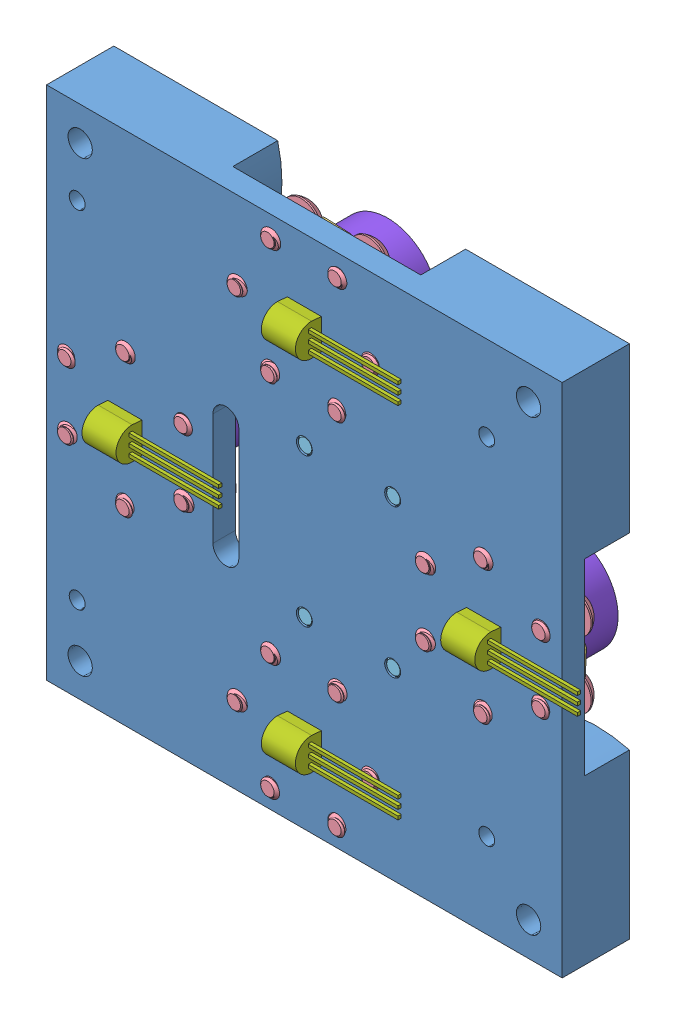
SolidWorks assembly LED Camera Assembly, configuration Default. Lengths in mm.
Overall size (79.31 74.9 15.88).
54 component instances, 9 part files, 49 mates.
Components (placement in the parent):
- Camera LED Holder Plate-1: Camera LED Holder Plate [Default] at (-0.0586 0.0315 12.2) x (1 0 0) z (0 1 0) size (73.03 9.53 73.03)
- RasPi_Camera-2: RasPi_Camera [Default] at (-0.0586 0.0315 4.3983) x (0 -1 0) z (1 0 0) size (25 8.25 24)
- COM-1318-5: COM-1318 [Default] at (-0.0586 -25.3685 9.025) x (0.998942 -0.045987 0) z (0.045987 0.998942 0) size (19.62 5.1 20.4)
- COM-1318-2: COM-1318 [Default] at (-25.4586 0.0315 9.025) x (0.888103 0.459645 0) z (-0.459645 0.888103 0) size (19.62 5.1 20.4)
- COM-1318-3: COM-1318 [Default] at (-0.0586 25.4315 9.025) x (0.998942 -0.045987 0) z (0.045987 0.998942 0) size (19.62 5.1 20.4)
- COM-1318-4: COM-1318 [Default] at (25.3414 0.0315 9.025) x (0.888103 0.459645 0) z (-0.459645 0.888103 0) size (19.62 5.1 20.4)
- 91255A105_ALLOY STEEL BUTTON-HEAD SOCKET CAP SCREW-1: 91255A105_ALLOY STEEL BUTTON-HEAD SOCKET CAP SCREW [91255A105] at (33.5686 -4.7185 6.4264) x (-0.805976 0.591949 0) z (0 0 -1) size (5.41 5.41 6.56)
- 91255A105_ALLOY STEEL BUTTON-HEAD SOCKET CAP SCREW-2: 91255A105_ALLOY STEEL BUTTON-HEAD SOCKET CAP SCREW [91255A105] at (25.3414 -9.4685 6.4264) x (0.109655 0.99397 0) z (0 0 -1) size (5.41 5.41 6.56)
- 91255A105_ALLOY STEEL BUTTON-HEAD SOCKET CAP SCREW-3: 91255A105_ALLOY STEEL BUTTON-HEAD SOCKET CAP SCREW [91255A105] at (17.1141 -4.7185 6.4264) x (0.91563 0.402021 0) z (0 0 -1) size (5.41 5.41 6.56)
- 91255A105_ALLOY STEEL BUTTON-HEAD SOCKET CAP SCREW-4: 91255A105_ALLOY STEEL BUTTON-HEAD SOCKET CAP SCREW [91255A105] at (17.1141 4.7815 6.4264) x (0.805976 -0.591949 0) z (0 0 -1) size (5.41 5.41 6.56)
- 91255A105_ALLOY STEEL BUTTON-HEAD SOCKET CAP SCREW-5: 91255A105_ALLOY STEEL BUTTON-HEAD SOCKET CAP SCREW [91255A105] at (25.3414 9.5315 6.4264) x (-0.109655 -0.99397 0) z (0 0 -1) size (5.41 5.41 6.56)
- 91255A105_ALLOY STEEL BUTTON-HEAD SOCKET CAP SCREW-6: 91255A105_ALLOY STEEL BUTTON-HEAD SOCKET CAP SCREW [91255A105] at (33.5686 4.7815 6.4264) x (-0.91563 -0.402021 0) z (0 0 -1) size (5.41 5.41 6.56)
- 91255A105_ALLOY STEEL BUTTON-HEAD SOCKET CAP SCREW-7: 91255A105_ALLOY STEEL BUTTON-HEAD SOCKET CAP SCREW [91255A105] at (-33.5686 -4.7185 6.4264) x (0.805976 0.591949 0) z (0 0 -1) size (5.41 5.41 6.56)
- 91255A105_ALLOY STEEL BUTTON-HEAD SOCKET CAP SCREW-8: 91255A105_ALLOY STEEL BUTTON-HEAD SOCKET CAP SCREW [91255A105] at (-25.3414 -9.4685 6.4264) x (-0.109655 0.99397 0) z (0 0 -1) size (5.41 5.41 6.56)
- 91255A105_ALLOY STEEL BUTTON-HEAD SOCKET CAP SCREW-9: 91255A105_ALLOY STEEL BUTTON-HEAD SOCKET CAP SCREW [91255A105] at (-17.1141 -4.7185 6.4264) x (0.91563 -0.402021 0) z (0 0 -1) size (5.41 5.41 6.56)
- 91255A105_ALLOY STEEL BUTTON-HEAD SOCKET CAP SCREW-10: 91255A105_ALLOY STEEL BUTTON-HEAD SOCKET CAP SCREW [91255A105] at (-17.1141 4.7815 6.4264) x (-0.805976 -0.591949 0) z (0 0 -1) size (5.41 5.41 6.56)
- 91255A105_ALLOY STEEL BUTTON-HEAD SOCKET CAP SCREW-11: 91255A105_ALLOY STEEL BUTTON-HEAD SOCKET CAP SCREW [91255A105] at (-25.3414 9.5315 6.4264) x (0.109655 -0.99397 0) z (0 0 -1) size (5.41 5.41 6.56)
- 91255A105_ALLOY STEEL BUTTON-HEAD SOCKET CAP SCREW-12: 91255A105_ALLOY STEEL BUTTON-HEAD SOCKET CAP SCREW [91255A105] at (-33.5686 4.7815 6.4264) x (-0.91563 0.402021 0) z (0 0 -1) size (5.41 5.41 6.56)
- 91255A105_ALLOY STEEL BUTTON-HEAD SOCKET CAP SCREW-13: 91255A105_ALLOY STEEL BUTTON-HEAD SOCKET CAP SCREW [91255A105] at (9.4414 25.4315 6.4264) x (-0.991393 -0.130919 0) z (0 0 -1) size (5.41 5.41 6.56)
- 91255A105_ALLOY STEEL BUTTON-HEAD SOCKET CAP SCREW-14: 91255A105_ALLOY STEEL BUTTON-HEAD SOCKET CAP SCREW [91255A105] at (4.6914 17.2043 6.4264) x (-0.609075 0.793112 0) z (0 0 -1) size (5.41 5.41 6.56)
- 91255A105_ALLOY STEEL BUTTON-HEAD SOCKET CAP SCREW-15: 91255A105_ALLOY STEEL BUTTON-HEAD SOCKET CAP SCREW [91255A105] at (-4.8086 17.2043 6.4264) x (0.382318 0.924031 0) z (0 0 -1) size (5.41 5.41 6.56)
- 91255A105_ALLOY STEEL BUTTON-HEAD SOCKET CAP SCREW-16: 91255A105_ALLOY STEEL BUTTON-HEAD SOCKET CAP SCREW [91255A105] at (-9.5586 25.4315 6.4264) x (0.991393 0.130919 0) z (0 0 -1) size (5.41 5.41 6.56)
- 91255A105_ALLOY STEEL BUTTON-HEAD SOCKET CAP SCREW-17: 91255A105_ALLOY STEEL BUTTON-HEAD SOCKET CAP SCREW [91255A105] at (-4.8086 33.6588 6.4264) x (0.609075 -0.793112 0) z (0 0 -1) size (5.41 5.41 6.56)
- 91255A105_ALLOY STEEL BUTTON-HEAD SOCKET CAP SCREW-18: 91255A105_ALLOY STEEL BUTTON-HEAD SOCKET CAP SCREW [91255A105] at (4.6914 33.6588 6.4264) x (-0.382318 -0.924031 0) z (0 0 -1) size (5.41 5.41 6.56)
- 91255A105_ALLOY STEEL BUTTON-HEAD SOCKET CAP SCREW-19: 91255A105_ALLOY STEEL BUTTON-HEAD SOCKET CAP SCREW [91255A105] at (9.4414 -25.4315 6.4264) x (-0.991393 0.130919 0) z (0 0 -1) size (5.41 5.41 6.56)
- 91255A105_ALLOY STEEL BUTTON-HEAD SOCKET CAP SCREW-20: 91255A105_ALLOY STEEL BUTTON-HEAD SOCKET CAP SCREW [91255A105] at (4.6914 -17.2043 6.4264) x (0.609075 0.793112 0) z (0 0 -1) size (5.41 5.41 6.56)
- 91255A105_ALLOY STEEL BUTTON-HEAD SOCKET CAP SCREW-21: 91255A105_ALLOY STEEL BUTTON-HEAD SOCKET CAP SCREW [91255A105] at (-4.8086 -17.2043 6.4264) x (0.382318 -0.924031 0) z (0 0 -1) size (5.41 5.41 6.56)
- 91255A105_ALLOY STEEL BUTTON-HEAD SOCKET CAP SCREW-22: 91255A105_ALLOY STEEL BUTTON-HEAD SOCKET CAP SCREW [91255A105] at (-9.5586 -25.4315 6.4264) x (0.991393 -0.130919 0) z (0 0 -1) size (5.41 5.41 6.56)
- 91255A105_ALLOY STEEL BUTTON-HEAD SOCKET CAP SCREW-23: 91255A105_ALLOY STEEL BUTTON-HEAD SOCKET CAP SCREW [91255A105] at (-4.8086 -33.6588 6.4264) x (-0.609075 -0.793112 0) z (0 0 -1) size (5.41 5.41 6.56)
- 91255A105_ALLOY STEEL BUTTON-HEAD SOCKET CAP SCREW-24: 91255A105_ALLOY STEEL BUTTON-HEAD SOCKET CAP SCREW [91255A105] at (4.6914 -33.6588 6.4264) x (-0.382318 0.924031 0) z (0 0 -1) size (5.41 5.41 6.56)
- 94735A152_BLACK NYLON PAN HEAD MACHINE SCREW-1: 94735A152_BLACK NYLON PAN HEAD MACHINE SCREW [94735A152] at (-0.0586 10.5315 4.95) x (-0.923728 -0.383049 0) z (0 0 -1) size (5.46 5.57 9.5)
- 94735A152_BLACK NYLON PAN HEAD MACHINE SCREW-2: 94735A152_BLACK NYLON PAN HEAD MACHINE SCREW [94735A152] at (12.4414 10.5315 4.95) x (-0.923728 -0.383049 0) z (0 0 -1) size (5.46 5.57 9.5)
- 94735A152_BLACK NYLON PAN HEAD MACHINE SCREW-3: 94735A152_BLACK NYLON PAN HEAD MACHINE SCREW [94735A152] at (-0.0586 -10.4685 4.95) x (-0.923728 -0.383049 0) z (0 0 -1) size (5.46 5.57 9.5)
- 94735A152_BLACK NYLON PAN HEAD MACHINE SCREW-4: 94735A152_BLACK NYLON PAN HEAD MACHINE SCREW [94735A152] at (12.4414 -10.4685 4.95) x (-0.923728 -0.383049 0) z (0 0 -1) size (5.46 5.57 9.5)
- 94639A702_NYLON UNTHRD SPACERS-1: 94639A702_NYLON UNTHRD SPACERS [94639A702] at (12.4414 -10.4685 7.4375) size (4.76 4.76 3.17)
- 94639A702_NYLON UNTHRD SPACERS-2: 94639A702_NYLON UNTHRD SPACERS [94639A702] at (-0.0586 -10.4685 7.4375) size (4.76 4.76 3.17)
- 94639A702_NYLON UNTHRD SPACERS-3: 94639A702_NYLON UNTHRD SPACERS [94639A702] at (12.4414 10.5315 7.4375) size (4.76 4.76 3.17)
- 94639A702_NYLON UNTHRD SPACERS-4: 94639A702_NYLON UNTHRD SPACERS [94639A702] at (-0.0586 10.5315 7.4375) size (4.76 4.76 3.17)
- MCP9701-1: MCP9701 [Default] at (-0.0586 -25.3685 13.597) x (0 -1 0) z (1 0 0) size (4.57 3.68 17.53)
- MCP9701-2: MCP9701 [Default] at (-0.0586 25.4315 13.597) x (0 -1 0) z (1 0 0) size (4.57 3.68 17.53)
- MCP9701-3: MCP9701 [Default] at (-25.4586 0.0315 13.597) x (0 -1 0) z (1 0 0) size (4.57 3.68 17.53)
- MCP9701-4: MCP9701 [Default] at (25.3414 0.0315 13.597) x (0 -1 0) z (1 0 0) size (4.57 3.68 17.53)
- Reflector-6: Reflector [Default] at (-4.2786 15.2111 10.2933) x (1 0 0) z (0 1 0) size (14.29 7.67 14.29)
  - Reflector Shell-1: Reflector Shell [Default] at (4.22 3.162 10.2204) size (14.29 12.7 14.29)
  - Reflector Core-1: Reflector Core [Default] at (4.22 3.162 10.2204) size (12.7 6.72 12.7)
- Reflector-9: Reflector [Default] at (15.2111 4.2786 10.2933) x (0 -1 0) z (1 0 0) size (14.29 7.67 14.29)
  - Reflector Shell-1: Reflector Shell [Default] at (4.22 3.162 10.2204) size (14.29 12.7 14.29)
  - Reflector Core-1: Reflector Core [Default] at (4.22 3.162 10.2204) size (12.7 6.72 12.7)
- Reflector-10: Reflector [Default] at (4.2786 -15.2111 10.2933) x (-1 0 0) z (0 -1 0) size (14.29 7.67 14.29)
  - Reflector Shell-1: Reflector Shell [Default] at (4.22 3.162 10.2204) size (14.29 12.7 14.29)
  - Reflector Core-1: Reflector Core [Default] at (4.22 3.162 10.2204) size (12.7 6.72 12.7)
- Reflector-11: Reflector [Default] at (-15.2111 -4.2786 10.2933) x (0 1 0) z (-1 0 0) size (14.29 7.67 14.29)
  - Reflector Shell-1: Reflector Shell [Default] at (4.22 3.162 10.2204) size (14.29 12.7 14.29)
  - Reflector Core-1: Reflector Core [Default] at (4.22 3.162 10.2204) size (12.7 6.72 12.7)
Mates (geometry in assembly coordinates):
- Coincident7: coincident anti-aligned: plane of COM-1318-2 through (-25.4586 0.0315 9.025) normal (0 0 1); plane of Camera LED Holder Plate-1 through (-0.0586 0.0315 9.025) normal (0 0 -1)
- Coincident8: coincident anti-aligned: plane of COM-1318-5 through (-0.0586 -25.3685 9.025) normal (0 0 1); plane of Camera LED Holder Plate-1 through (-0.0586 0.0315 9.025) normal (0 0 -1)
- Coincident9: coincident anti-aligned: plane of COM-1318-3 through (-0.0586 25.4315 9.025) normal (0 0 1); plane of Camera LED Holder Plate-1 through (-0.0586 0.0315 9.025) normal (0 0 -1)
- Coincident10: coincident anti-aligned: plane of COM-1318-4 through (25.3414 0.0315 9.025) normal (0 0 1); plane of Camera LED Holder Plate-1 through (-0.0586 0.0315 9.025) normal (0 0 -1)
- Concentric61: concentric aligned: cylinder of Camera LED Holder Plate-1 through (12.4414 -10.4685 9.025) axis (0 0 -1) radius 1.1303; cylinder of RasPi_Camera-2 through (12.4414 -10.4685 5.85) axis (0 0 -1) radius 1.05
- Concentric62: concentric aligned: cylinder of Camera LED Holder Plate-1 through (12.4414 10.5315 9.025) axis (0 0 -1) radius 1.1303; cylinder of RasPi_Camera-2 through (12.4414 10.5315 5.85) axis (0 0 -1) radius 1.05
- Coincident73: coincident anti-aligned: plane of COM-1318-4 through (25.3414 0.0315 7.925) normal (0 0 -1); plane of 91255A105_ALLOY STEEL BUTTON-HEAD SOCKET CAP SCREW-1 through (31.9673 -6.8987 7.925) normal (0 0 1)
- Coincident74: coincident: axis of RasPi_Camera-2 through (0 0 1) axis (0 0 -1); plane of assembly
- Coincident75: coincident: axis of RasPi_Camera-2 through (0 0 1) axis (0 0 -1); plane of assembly
- Parallel5: parallel aligned: plane of Camera LED Holder Plate-1 through (-36.5711 36.544 9.025) normal (0 1 0); plane of assembly through (0 0 0) normal (0 1 0)
- Coincident77: coincident anti-aligned: plane of RasPi_Camera-2 through (0 -1 0) normal (0 0 -1); plane of assembly through (0 0 0) normal (0 0 1)
- Coincident78: coincident anti-aligned: plane of COM-1318-3 through (-0.0586 25.4315 7.925) normal (0 0 -1); plane of 91255A105_ALLOY STEEL BUTTON-HEAD SOCKET CAP SCREW-13 through (9.7955 22.7497 7.925) normal (0 0 1)
- Concentric78: concentric aligned: cylinder of Camera LED Holder Plate-1 through (9.4414 25.4315 9.025) axis (0 0 -1) radius 1.1303; circle of 91255A105_ALLOY STEEL BUTTON-HEAD SOCKET CAP SCREW-13
- Concentric79: concentric aligned: cylinder of Camera LED Holder Plate-1 through (4.6914 -33.5957 9.025) axis (0 0 -1) radius 1.1303; cylinder of COM-1318-5 through (4.6914 -33.5957 9.025) axis (0 0 -1) radius 2
- Concentric80: concentric aligned: cylinder of Camera LED Holder Plate-1 through (-4.8086 -33.5957 9.025) axis (0 0 -1) radius 1.1303; cylinder of COM-1318-5 through (-4.8086 -33.5957 9.025) axis (0 0 -1) radius 2
- Concentric81: concentric aligned: cylinder of Camera LED Holder Plate-1 through (-17.2314 -4.7185 9.025) axis (0 0 -1) radius 1.1303; cylinder of COM-1318-2 through (-17.2314 -4.7185 9.025) axis (0 0 -1) radius 2
- Concentric82: concentric aligned: cylinder of Camera LED Holder Plate-1 through (-25.4586 -9.4685 9.025) axis (0 0 -1) radius 1.1303; cylinder of COM-1318-2 through (-25.4586 -9.4685 9.025) axis (0 0 -1) radius 2
- Concentric83: concentric aligned: cylinder of Camera LED Holder Plate-1 through (4.6914 17.2043 9.025) axis (0 0 -1) radius 1.1303; cylinder of COM-1318-3 through (4.6914 17.2043 9.025) axis (0 0 -1) radius 2
- Concentric85: concentric aligned: cylinder of Camera LED Holder Plate-1 through (25.3414 -9.4685 9.025) axis (0 0 -1) radius 1.1303; cylinder of COM-1318-4 through (25.3414 -9.4685 9.025) axis (0 0 -1) radius 2
- Concentric86: concentric aligned: cylinder of Camera LED Holder Plate-1 through (17.1141 -4.7185 9.025) axis (0 0 -1) radius 1.1303; cylinder of COM-1318-4 through (17.1141 -4.7185 9.025) axis (0 0 -1) radius 2
- Concentric87: concentric aligned: cylinder of Camera LED Holder Plate-1 through (33.5686 -4.7185 9.025) axis (0 0 -1) radius 1.1303; circle of 91255A105_ALLOY STEEL BUTTON-HEAD SOCKET CAP SCREW-1
- Concentric89: concentric aligned: cylinder of COM-1318-3 through (-9.5586 25.4315 9.025) axis (0 0 -1) radius 2; cylinder of Camera LED Holder Plate-1 through (-9.5586 25.4315 9.025) axis (0 0 -1) radius 1.1303
- Coincident79: coincident anti-aligned: plane of Camera LED Holder Plate-1 through (-0.0586 0.0315 9.025) normal (0 0 -1); plane of 94639A702_NYLON UNTHRD SPACERS-2 through (-0.0586 -10.4685 9.025) normal (0 0 1)
- Concentric90: concentric anti-aligned: cylinder of Camera LED Holder Plate-1 through (-0.0586 -10.4685 9.025) axis (0 0 -1) radius 1.1303; circle of 94639A702_NYLON UNTHRD SPACERS-2
- Coincident80: coincident anti-aligned: plane of Camera LED Holder Plate-1 through (-0.0586 0.0315 9.025) normal (0 0 -1); plane of 94639A702_NYLON UNTHRD SPACERS-4 through (-0.0586 10.5315 9.025) normal (0 0 1)
- Concentric91: concentric anti-aligned: cylinder of Camera LED Holder Plate-1 through (-0.0586 10.5315 9.025) axis (0 0 -1) radius 1.1303; circle of 94639A702_NYLON UNTHRD SPACERS-4
- Coincident81: coincident anti-aligned: plane of Camera LED Holder Plate-1 through (-0.0586 0.0315 9.025) normal (0 0 -1); plane of 94639A702_NYLON UNTHRD SPACERS-1 through (12.4414 -10.4685 9.025) normal (0 0 1)
- Concentric92: concentric aligned: cylinder of Camera LED Holder Plate-1 through (12.4414 -10.4685 9.025) axis (0 0 -1) radius 1.1303; cylinder of 94639A702_NYLON UNTHRD SPACERS-1 through (12.4414 -10.4685 9.025) axis (0 0 -1) radius 2.3813
- Coincident82: coincident anti-aligned: plane of Camera LED Holder Plate-1 through (-0.0586 0.0315 9.025) normal (0 0 -1); plane of 94639A702_NYLON UNTHRD SPACERS-3 through (12.4414 10.5315 9.025) normal (0 0 1)
- Concentric93: concentric aligned: cylinder of Camera LED Holder Plate-1 through (12.4414 10.5315 9.025) axis (0 0 -1) radius 1.1303; cylinder of 94639A702_NYLON UNTHRD SPACERS-3 through (12.4414 10.5315 9.025) axis (0 0 -1) radius 2.3813
- Coincident83: coincident anti-aligned: plane of RasPi_Camera-2 through (-0.0586 0.0315 5.85) normal (0 0 1); plane of 94639A702_NYLON UNTHRD SPACERS-3 through (12.4414 10.5315 5.85) normal (0 0 -1)
- Coincident84: coincident anti-aligned: plane of RasPi_Camera-2 through (-0.0586 0.0315 4.95) normal (0 0 -1); plane of 94735A152_BLACK NYLON PAN HEAD MACHINE SCREW-4 through (12.4414 -10.4685 4.95) normal (0 0 1)
- Concentric94: concentric anti-aligned: circle of RasPi_Camera-2; cylinder of 94735A152_BLACK NYLON PAN HEAD MACHINE SCREW-4 through (12.4414 -10.4685 3.045) axis (0 0 1) radius 2.7305
- Coincident85: coincident anti-aligned: plane of RasPi_Camera-2 through (-0.0586 0.0315 4.95) normal (0 0 -1); plane of 94735A152_BLACK NYLON PAN HEAD MACHINE SCREW-3 through (-0.0586 -10.4685 4.95) normal (0 0 1)
- Concentric95: concentric anti-aligned: circle of RasPi_Camera-2; cylinder of 94735A152_BLACK NYLON PAN HEAD MACHINE SCREW-3 through (-0.0586 -10.4685 3.045) axis (0 0 1) radius 2.7305
- Coincident86: coincident anti-aligned: plane of RasPi_Camera-2 through (-0.0586 0.0315 4.95) normal (0 0 -1); plane of 94735A152_BLACK NYLON PAN HEAD MACHINE SCREW-2 through (12.4414 10.5315 4.95) normal (0 0 1)
- Concentric96: concentric anti-aligned: circle of RasPi_Camera-2; cylinder of 94735A152_BLACK NYLON PAN HEAD MACHINE SCREW-2 through (12.4414 10.5315 3.045) axis (0 0 1) radius 2.7305
- Coincident87: coincident anti-aligned: plane of RasPi_Camera-2 through (-0.0586 0.0315 4.95) normal (0 0 -1); plane of 94735A152_BLACK NYLON PAN HEAD MACHINE SCREW-1 through (-0.0586 10.5315 4.95) normal (0 0 1)
- Concentric97: concentric anti-aligned: cylinder of RasPi_Camera-2 through (-0.0586 10.5315 5.85) axis (0 0 -1) radius 1.05; circle of 94735A152_BLACK NYLON PAN HEAD MACHINE SCREW-1
- Coincident88: coincident anti-aligned: plane of Camera LED Holder Plate-1 through (-0.0586 0.0315 12.2) normal (0 0 1); plane of MCP9701-1 through (2.3544 -23.2047 12.2) normal (0 0 -1)
- Coincident89: coincident anti-aligned: plane of Camera LED Holder Plate-1 through (-0.0586 0.0315 12.2) normal (0 0 1); plane of MCP9701-2 through (2.3544 27.5953 12.2) normal (0 0 -1)
- Coincident90: coincident anti-aligned: plane of Camera LED Holder Plate-1 through (-0.0586 0.0315 12.2) normal (0 0 1); plane of MCP9701-3 through (-23.0456 2.1953 12.2) normal (0 0 -1)
- Coincident91: coincident anti-aligned: plane of Camera LED Holder Plate-1 through (-0.0586 0.0315 12.2) normal (0 0 1); plane of MCP9701-4 through (27.7544 2.1953 12.2) normal (0 0 -1)
- Parallel14: parallel anti-aligned: plane of Camera LED Holder Plate-1 through (36.4539 -36.481 9.025) normal (1 0 0); plane of MCP9701-1 through (-2.4716 -25.3685 13.597) normal (-1 0 0)
- Parallel15: parallel anti-aligned: plane of Camera LED Holder Plate-1 through (36.4539 -36.481 9.025) normal (1 0 0); plane of MCP9701-2 through (-2.4716 25.4315 13.597) normal (-1 0 0)
- Parallel16: parallel anti-aligned: plane of Camera LED Holder Plate-1 through (36.4539 -36.481 9.025) normal (1 0 0); plane of MCP9701-3 through (-27.8716 0.0315 13.597) normal (-1 0 0)
- Parallel17: parallel anti-aligned: plane of Camera LED Holder Plate-1 through (36.4539 -36.481 9.025) normal (1 0 0); plane of MCP9701-4 through (22.9284 0.0315 13.597) normal (-1 0 0)
- Coincident92: coincident anti-aligned: plane of COM-1318-3 through (-0.0586 25.4315 7.925) normal (0 0 -1); plane of Reflector-6/Reflector Shell-1 through (-0.0586 25.4315 7.925) normal (0 0 1)
- Concentric98: concentric aligned: cylinder of COM-1318-3 through (-0.0586 25.4315 -7.4887) axis (0 0 1) radius 4; cylinder of Reflector-6/Reflector Shell-1 through (-0.0586 25.4315 254.4166) axis (0 0 1) radius 7.1437
